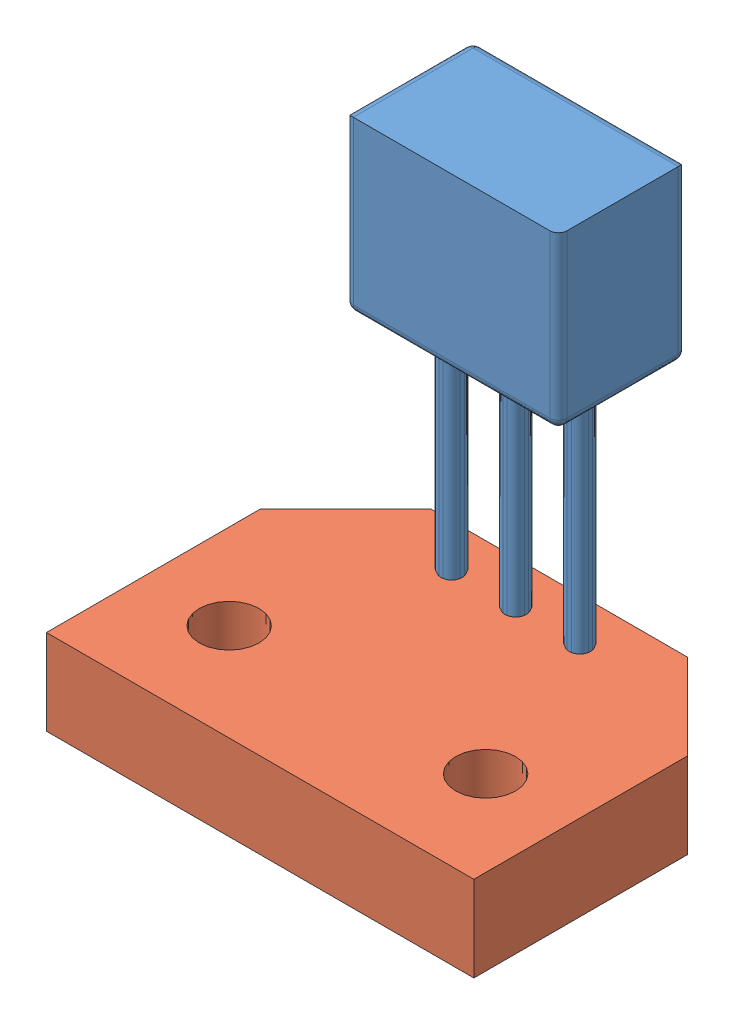
SolidWorks assembly rpm-sensing, configuration Default. Lengths in mm.
Overall size (10 12 7.53).
2 component instances, 2 part files, 3 mates.
Components (placement in the parent):
- hall-effect-sensor-1: hall-effect-sensor [Default] at (40.2355 -15.1857 1.775) size (5 12 3)
- hall-effect-stand-1: hall-effect-stand [Default] at (-13.4985 -4.5329 9.3043) x (1 0 0) z (0 1 0) size (10 7 2)
Mates (geometry in assembly coordinates):
- Concentric6: concentric: cylinder of hall-effect-sensor-1 through (-5.9014 -5.0329 3.325) axis (0 1 0) radius 0.2; cylinder of hall-effect-stand-1 through (-5.9014 -9.0375 3.325) axis (0 1 0) radius 0.25
- Concentric7: concentric: cylinder of hall-effect-sensor-1 through (-7.4014 -5.0329 3.325) axis (0 1 0) radius 0.2; cylinder of hall-effect-stand-1 through (-7.4014 -9.0375 3.325) axis (0 1 0) radius 0.25
- Distance1: distance = 5.5 mm anti-aligned: plane of hall-effect-sensor-1 through (-9.9514 2.9671 4.775) normal (0 -1 0); plane of hall-effect-stand-1 through (-13.4985 -2.5329 9.3043) normal (0 1 0)
